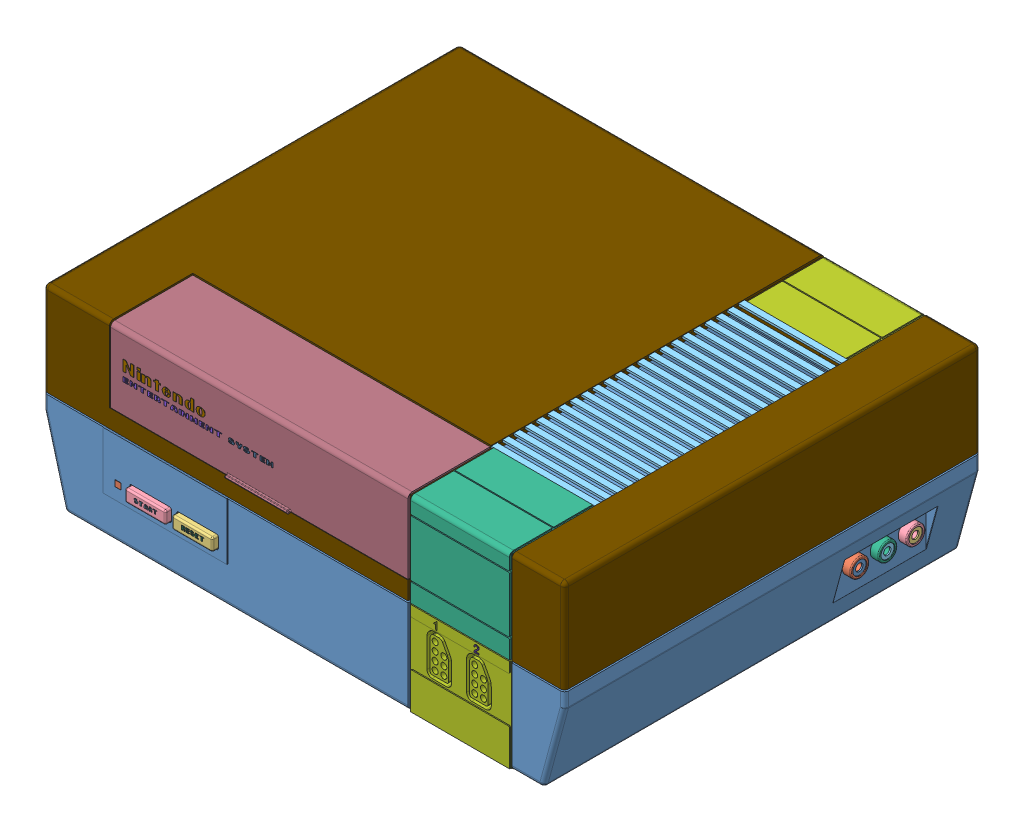
SolidWorks assembly Nintendo 8 bit console, configuration Default. Lengths in mm.
Overall size (250.5 90.25 203.12).
29 component instances, 25 part files, 0 mates.
Components (placement in the parent):
- Bottom-1: Bottom [Default] at origin size (250.5 45.25 200.5)
- Red Buttpn-1: Red Buttpn [Default] at (-178.966 -0.8885 194.9444) size (2.83 2.83 5.61)
- ResetButton-1: ResetButton [Default] at origin size (19.5 6 7.51)
- Power Button-1: Power Button [Default] at (-163.2927 -1.1385 195.5676) size (19.5 6 7.51)
- Part86-1: Part86 [Default] at (10 64.4444 160) x (0 0 -1) z (1 0 0) size (121.8 1 51)
- Part54-1: Part54 [Default] at (-20 38.9444 199) size (48.5 44.75 40)
- ControllPlate-1: ControllPlate [Default] at (-15 -3.0556 199) size (50 44.75 13)
- Nintendo Text-1: Nintendo Text [Default] at origin size (72.21 9.55 0.13)
  - Text3D - ENTERTAINMENT-1: Text3D - ENTERTAINMENT [Default] at (-177.0237 42.8806 189.646) x (-1 0 0) z (0 0 1) size (47.5 2.19 0.13)
  - Text3D - Nintendo-1: Text3D - Nintendo [Default] at (-177.0237 47.1471 200) x (-1 0 0) z (0 0 1) size (39.5 5.28 0.13)
  - Text3D - SYSTEM-1: Text3D - SYSTEM [Default] at (-126.3184 42.989 188.4705) x (-1 0 0) z (0 0 1) size (21.5 2.18 0.13)
- Part233-1: Part233 [Default] at (-4.6473 -10.2448 10) x (1 0 0) z (0 0 -1) size (6.16 6.16 4.76)
- Part235-1: Part235 [Default] at (-19.8999 -10.2448 10) x (1 0 0) z (0 0 -1) size (8 16 4.76)
- Hatch-1: Hatch [Default] at (-116.4375 28.9444 160) size (143 36 41)
- Text3D - START-1: Text3D - START [Default] at (-168.5955 -1.6899 203.0745) x (-1 0 0) z (0 0 1) size (11 1.9 0.04)
- Text3D - RESET-1: Text3D - RESET [Default] at (-145.7063 -1.6899 203.0745) x (-1 0 0) z (0 0 1) size (10.58 2 0.04)
- Text3D - 1-1: Text3D - 1 [Default] at (-27.5295 14.584 200) x (-1 0 0) z (0 0 1) size (1.58 3.74 0.13)
- Text3D - 2-1: Text3D - 2 [Default] at (-8.2516 14.584 200) x (-1 0 0) z (0 0 1) size (2.5 3.6 0.13)
- Top-1: Top [Default] at (-90 19.6944 0) x (1 0 0) z (0 0 -1) size (250.5 44.75 200)
- 3,5 mm (Audio White)-1: 3,5 mm (Audio White) [Default] at (-1.2891 -2.1559 13.5) size (4.05 9 9)
  - Part216-1: Part216 [Default] at (32.1699 -0.8638 41.0298) x (0 1 0) z (1 0 0) size (6.48 6.48 0.63)
  - Part215-1: Part215 [Default] at (29.0831 -0.8638 41.0298) x (0 1 0) z (1 0 0) size (9 9 4.05)
- 3,5 mm (Video Yellow)-1: 3,5 mm (Video Yellow) [Default] at (-1.2891 -2.1559 -13.5) size (4.05 9 9)
  - Part216_2-1: Part216_2 [Default] at (32.1699 -0.8638 41.0298) x (0 1 0) z (1 0 0) size (6.48 6.48 0.63)
  - Part215_2-1: Part215_2 [Default] at (29.0831 -0.8638 41.0298) x (0 1 0) z (1 0 0) size (9 9 4.05)
- 3,5 mm (Video Red)-1: 3,5 mm (Video Red) [Default] at (-1.2891 -2.1559 0) size (4.05 9 9)
  - Part216_3-1: Part216_3 [Default] at (32.1699 -0.8638 41.0298) x (0 1 0) z (1 0 0) size (6.48 6.48 0.63)
  - Part215_3-1: Part215_3 [Default] at (29.0831 -0.8638 41.0298) x (0 1 0) z (1 0 0) size (9 9 4.05)
- Part54_2-1: Part54_2 [Default] at origin size (48.5 44.75 38.2)
